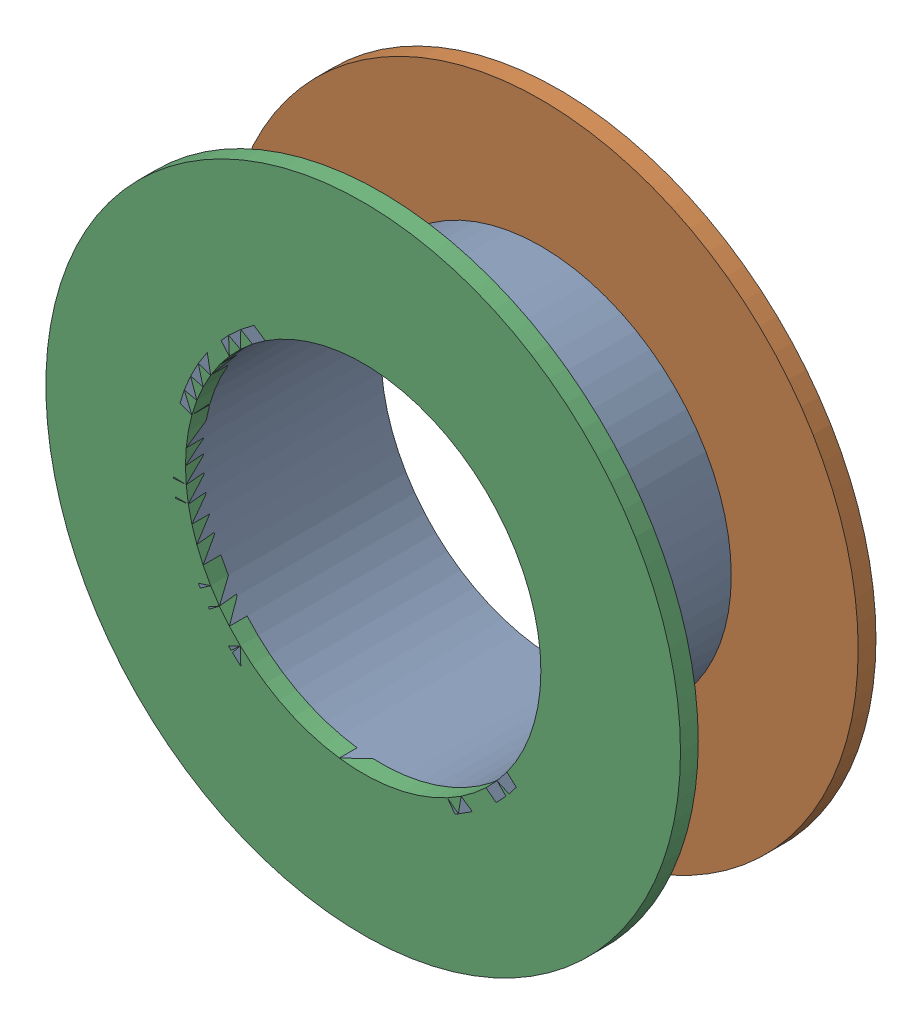
SolidWorks assembly Via (24.5mm,58.5mm) from Top Layer to Bottom Layer, configuration Predeterminado. Lengths in mm.
Overall size (1.27 1.27 0.39).
6 component instances, 2 part files, 0 mates.
Components (placement in the parent):
- Via Hole-1: Via Hole [Predeterminado] at (24.5 58.5 -0.4013) size (0.76 0.76 0.39)
  - Via Hole-Part-1-1: Via Hole-Part-1 [Predeterminado] at origin size (0.76 0.76 0.39)
- Via Top Layer-1: Via Top Layer [Predeterminado] at (24.5 58.5 -0.4013) size (1.27 1.27 0.04)
  - Via Top Layer-Part-1-1: Via Top Layer-Part-1 [Predeterminado] at origin size (1.27 1.27 0.04)
- Via Top Layer-2: Via Top Layer [Predeterminado] at (24.5 58.5 -0.0457) size (1.27 1.27 0.04)
  - Via Top Layer-Part-1-1: Via Top Layer-Part-1 [Predeterminado] at origin size (1.27 1.27 0.04)
